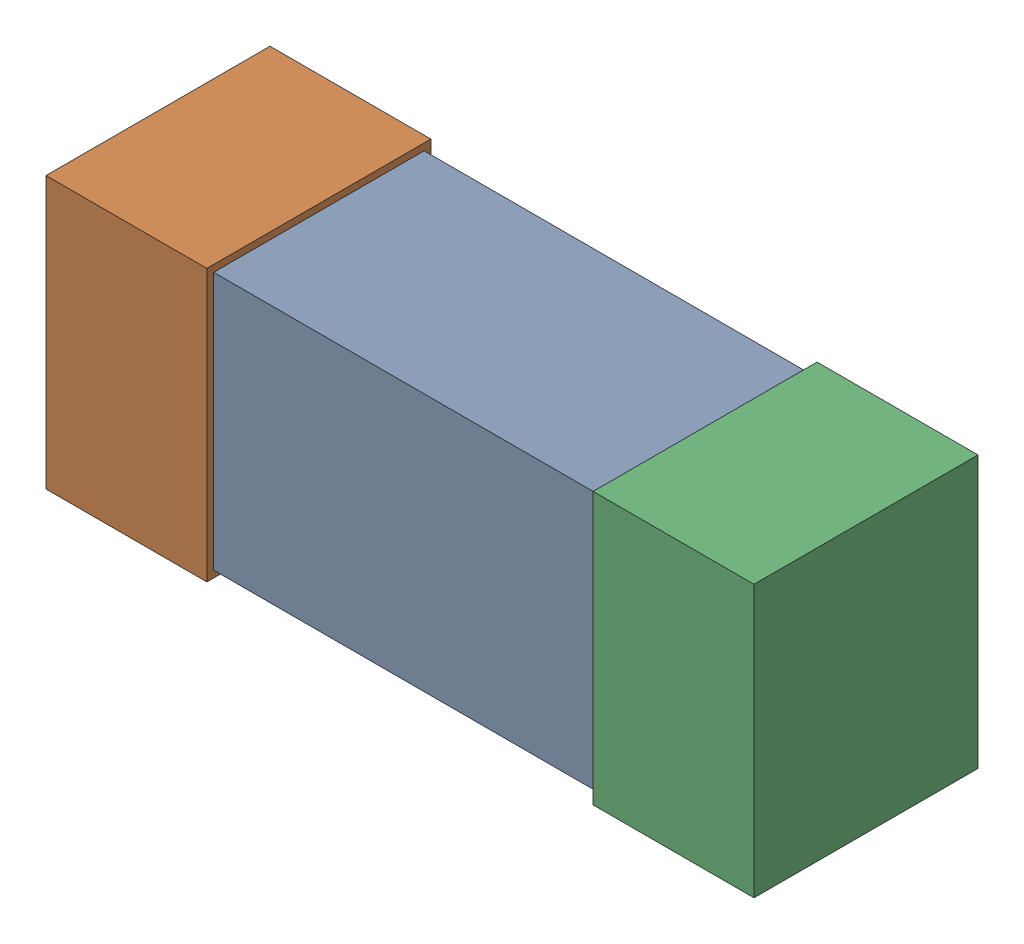
SolidWorks assembly C2, configuration Default. Lengths in mm.
Overall size (1.04 0.4 0.33).
4 component instances, 3 part files, 0 mates.
Components (placement in the parent):
- Open CASCADE STEP translator 6.8 1.3.1-1: Open CASCADE STEP translator 6.8 1.3.1 [Default] at origin size (1.04 0.4 0.33)
  - Body_1_3-1: Body_1_3 [Default] at origin size (0.73 0.38 0.31)
  - Pin_1-1: Pin_1 [Default] at origin size (0.24 0.4 0.33)
  - Pin_2-1: Pin_2 [Default] at (1.506 0 0) x (-1 0 0) z (0 0 1) size (0.24 0.4 0.33)
